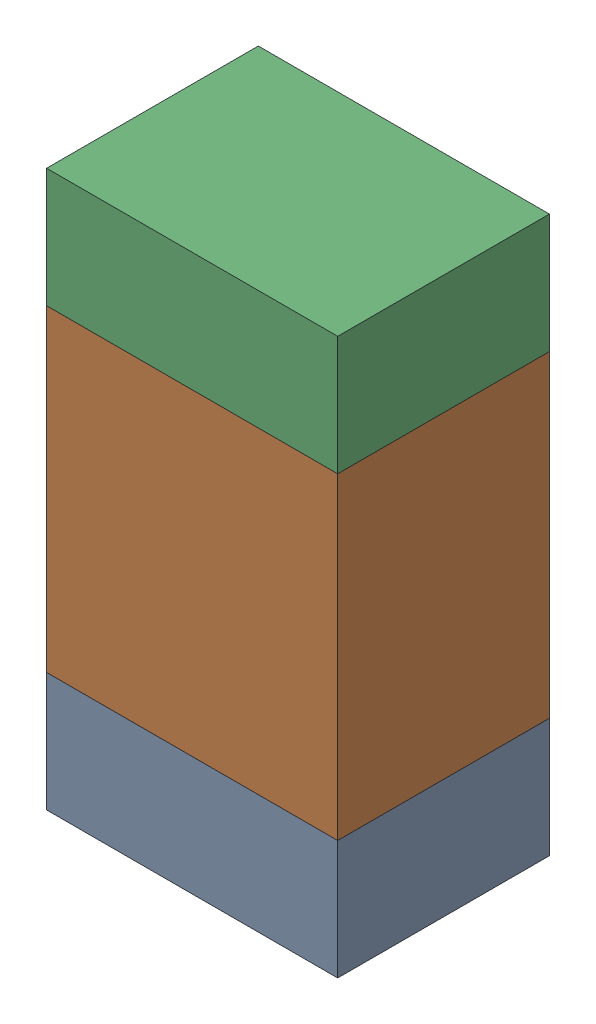
SolidWorks assembly R320_1PCB, configuration Default. Lengths in mm.
Overall size (0.55 1.05 0.4).
6 component instances, 2 part files, 0 mates.
Components (placement in the parent):
- 846483288-1: 846483288 [Default] at (128.9999 115.0874 -2.0638) size (0.55 0.22 0.4)
  - Extruded_12-1: Extruded_12 [Default] at origin size (0.55 0.22 0.4)
- 846483424-1: 846483424 [Default] at (128.9999 115.4999 -2.0638) size (0.55 0.6 0.4)
  - Extruded_13-1: Extruded_13 [Default] at origin size (0.55 0.6 0.4)
- 846483288-2: 846483288 [Default] at (128.9999 115.9124 -2.0638) size (0.55 0.22 0.4)
  - Extruded_12-1: Extruded_12 [Default] at origin size (0.55 0.22 0.4)
